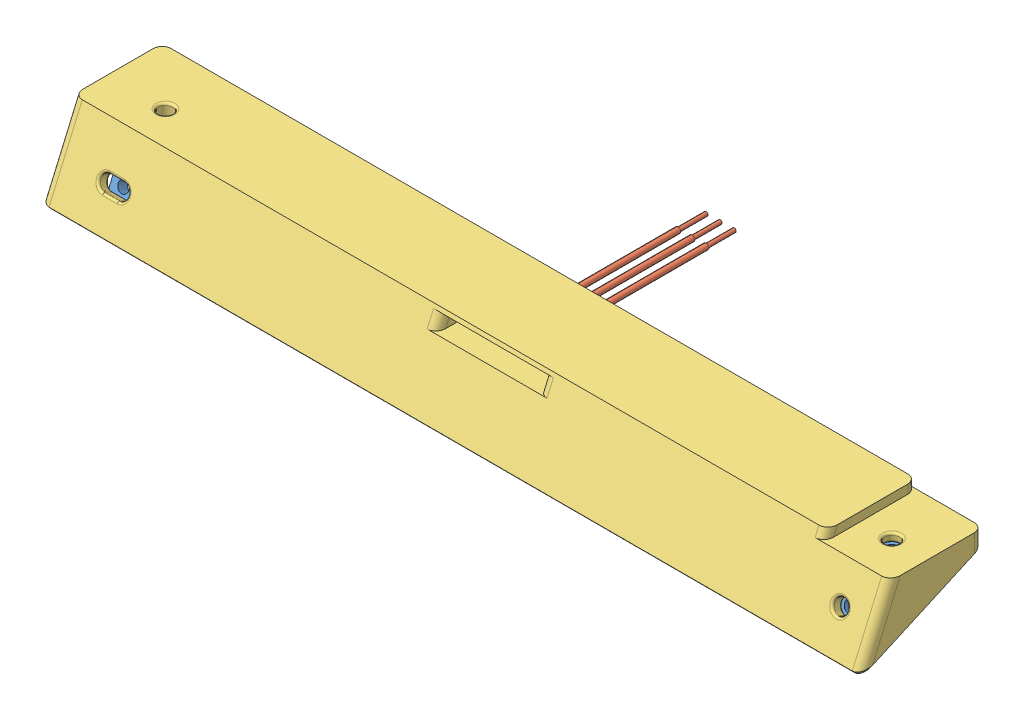
SolidWorks assembly 040M01C04P000 HES Mount, configuration Predeterminado. Lengths in mm.
Overall size (185 18.02 58.22).
6 component instances, 3 part files, 12 mates.
Components (placement in the parent):
- DIN934 M3-1: DIN934 M3 [Predeterminado] at (81.85 -5.6 -0.0765) x (0.866025 0 0.5) z (-0.5 0 0.866025) size (6.35 2.4 5.5)
- DIN934 M3-2: DIN934 M3 [Predeterminado] at (-81.85 -5.6 -0.0765) x (-0.866025 0 -0.5) z (0.5 0 -0.866025) size (6.35 2.4 5.5)
- DIN934 M3-5: DIN934 M3 [Predeterminado] at (81.85 -9.6504 9.3179) x (-0.866025 -0.45853 0.199375) z (0.5 -0.794197 0.345327) size (6.35 2.4 5.5)
- DIN934 M3-4: DIN934 M3 [Predeterminado] at (-81.85 -9.6504 9.3179) x (-0.866025 -0.45853 0.199375) z (0.5 -0.794197 0.345327) size (6.35 2.4 5.5)
- NPN Hall Effect Sensor (RS=765-9325)-1: NPN Hall Effect Sensor (RS=765-9325) [Default] x (0 0 -1) z (1 0 0) size (49.02 3.3 21.84)
- 040M01C04P002B Sensor Mount-2: 040M01C04P002B Sensor Mount [Predeterminado] at origin size (185 18.02 27.49)
Mates (geometry in assembly coordinates):
- Concentric1: concentric: cylinder of DIN934 M3-1 through (81.85 -3.2 -0.0765) axis (0 -1 0) radius 1.25; cylinder of 040M01C04P002B Sensor Mount-2 through (81.85 -17.5422 -0.0765) axis (0 1 0) radius 1.65
- Coincident13: coincident: plane of DIN934 M3-1 through (81.85 -3.2 -3.2519) normal (0 1 0); plane of 040M01C04P002B Sensor Mount-2 through (0 -3.2 0) normal (0 -1 0)
- Parallel1: parallel: plane of DIN934 M3-1 through (84.6 -3.2 1.5112) normal (1 0 0); plane of 040M01C04P002B Sensor Mount-2 through (84.65 -17.5412 1.5401) normal (-1 0 0)
- Concentric2: concentric: cylinder of DIN934 M3-2 through (-81.85 -3.2 -0.0765) axis (0 -1 0) radius 1.25; cylinder of 040M01C04P002B Sensor Mount-2 through (-81.85 -17.5422 -0.0765) axis (0 1 0) radius 1.65
- Coincident15: coincident: plane of DIN934 M3-2 through (-81.85 -3.2 3.0989) normal (0 1 0); plane of 040M01C04P002B Sensor Mount-2 through (0 -3.2 0) normal (0 -1 0)
- Parallel2: parallel: plane of DIN934 M3-2 through (-84.6 -3.2 -1.6642) normal (-1 0 0); plane of 040M01C04P002B Sensor Mount-2 through (-84.65 -17.5412 -1.6931) normal (1 0 0)
- Concentric3: concentric: cylinder of DIN934 M3-5 through (81.85 -10.6074 7.1169) axis (0 0.398749 0.91706) radius 1.25; cylinder of 040M01C04P002B Sensor Mount-2 through (81.85 -18.8838 -11.9176) axis (0 0.398749 0.91706) radius 1.65
- Coincident17: coincident: plane of DIN934 M3-5 through (81.85 -6.7383 8.0517) normal (0 0.398749 0.91706); plane of 040M01C04P002B Sensor Mount-2 through (81.85 -9.6504 9.3179) normal (0 -0.398749 -0.91706)
- Parallel3: parallel: plane of DIN934 M3-5 through (84.6 -9.1513 6.4838) normal (1 0 0); plane of 040M01C04P002B Sensor Mount-2 through (90 0.8 0) normal (1 0 0)
- Slot1: slot: cylinder of DIN934 M3-4 through (-81.85 -10.6074 7.1169) axis (0 0.398749 0.91706) radius 1.25; plane of 040M01C04P002B Sensor Mount-2 through (0 -20.397 -11.2597) normal (0 0.91706 -0.398749); cylinder of 040M01C04P002B Sensor Mount-2 through (-83.5 -18.8838 -11.9176) axis (0 0.398749 0.91706) radius 1.65
- Coincident19: coincident: plane of DIN934 M3-4 through (-81.85 -6.7383 8.0517) normal (0 0.398749 0.91706); plane of 040M01C04P002B Sensor Mount-2 through (-85.15 -9.6504 9.3179) normal (0 -0.398749 -0.91706)
- Parallel4: parallel: plane of DIN934 M3-4 through (-84.6 -12.0634 7.75) normal (-1 0 0); plane of 040M01C04P002B Sensor Mount-2 through (-95 0.8 0) normal (-1 0 0)
